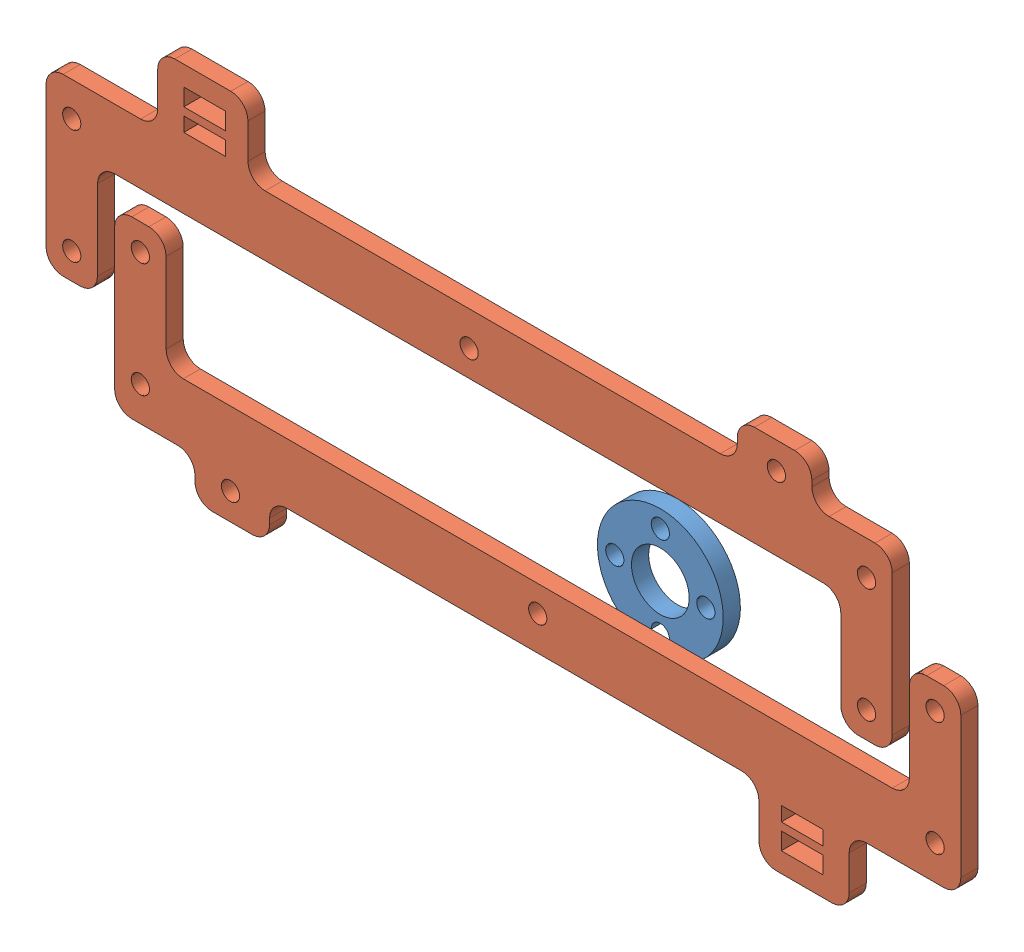
SolidWorks assembly BED THING, configuration Default. Lengths in mm.
Overall size (160 70.36 3).
3 component instances, 2 part files, 4 mates.
Components (placement in the parent):
- Mini CF Z nut atachment-1: Mini CF Z nut atachment [Valor predeterminado] at (81.1617 -310.0342 -88.0507) x (-1 0 0) z (0 0 1) size (22 19.05 3)
- TABLE2-1: TABLE2 [Valor predeterminado] at (-38.54 207.4746 -88.0507) size (148 42.68 3)
- TABLE2-2: TABLE2 [Valor predeterminado] at (-61.3122 -219.0612 -88.0507) x (-1 0 0) z (0 0 1) size (148 42.68 3)
Mates (geometry in assembly coordinates):
- Coincident2: coincident aligned: plane of TABLE2-1 through (-134.9893 -25.8799 -85.0507) normal (0 0 1); plane of TABLE2-2 through (35.1371 14.2933 -85.0507) normal (0 0 1)
- Coincident4: coincident aligned: plane of Mini CF Z nut atachment-1 through (-22.4849 -7.2683 -85.0507) normal (0 0 1); plane of TABLE2-1 through (-134.9893 -25.8799 -85.0507) normal (0 0 1)
- Distance2: distance = 3 mm anti-aligned: plane of TABLE2-2 through (18.0739 -13.2952 -95.0507) normal (1 0 0); plane of TABLE2-1 through (21.0739 1.7086 -95.0507) normal (-1 0 0)
- Distance3: distance = 3 mm anti-aligned: plane of Mini CF Z nut atachment-1 through (-14.9884 -15.3183 -85.0507) normal (0 -1 0); plane of TABLE2-1 through (-108.9261 -18.3183 -95.0507) normal (0 1 0)
